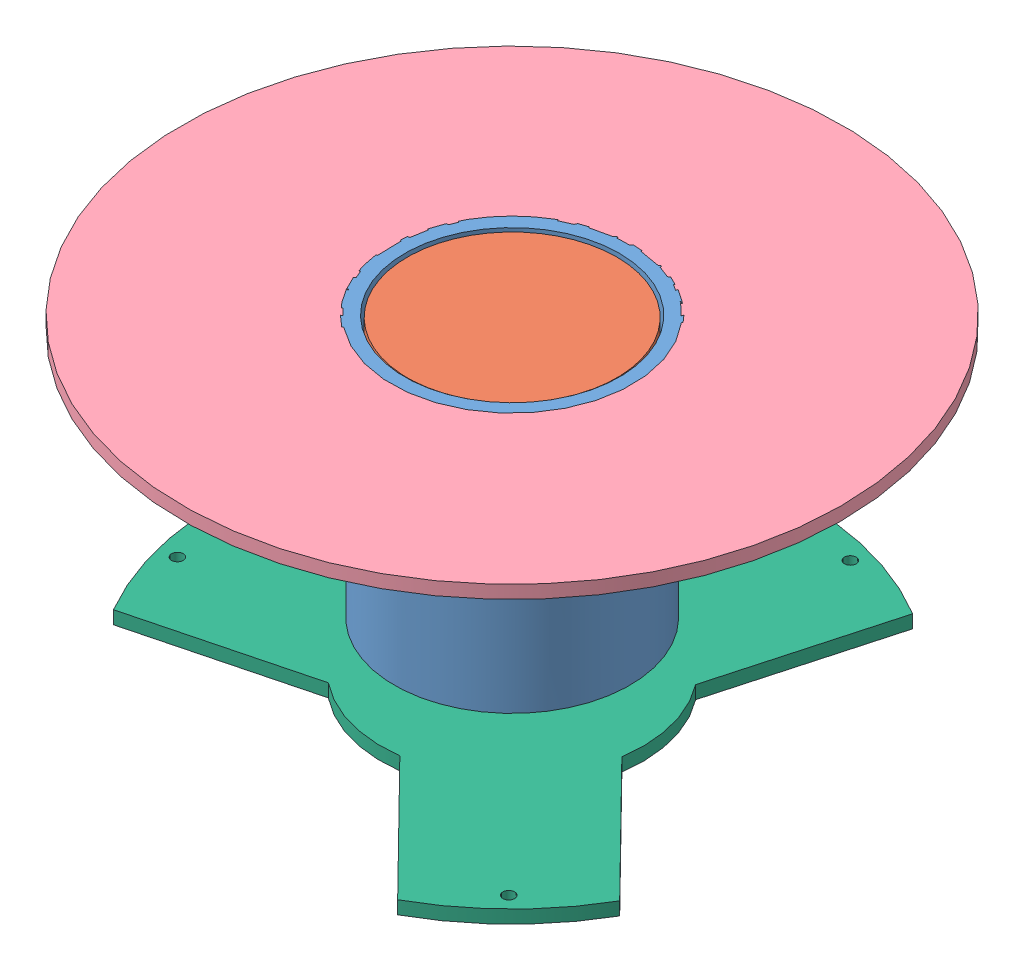
SolidWorks assembly SmallBuildSystem, configuration Default. Lengths in mm.
Overall size (310.19 197.05 310.19).
6 component instances, 6 part files, 10 mates.
Components (placement in the parent):
- SmallBuildCylinder-1: SmallBuildCylinder [Default] at origin size (92.82 100 92.82)
- 80mmBuildPlate-1: 80mmBuildPlate [Default] at (0 -15.7417 0) size (80 15 80)
- SmallBuildBase-1: SmallBuildBase [Default] at (0 -45.7417 0) x (0.949791 0 0.312884) z (-0.312884 0 0.949791) size (80 30 80)
- FillerPlate-1: FillerPlate [Default] x (0.963615 0 0.267294) z (-0.267294 0 0.963615) size (252 5 252)
- BaseRod-1: BaseRod [Default] at (0 -122.7417 0) x (-0.344051 0 -0.938951) z (0.938951 0 -0.344051) size (15 105 15)
- BuildBaseAdapter-1: BuildBaseAdapter [Default] at (0 -122.7417 0) x (0.963615 0 0.267294) z (-0.267294 0 0.963615) size (216 5 191.17)
Mates (geometry in assembly coordinates):
- Concentric1: concentric aligned: cylinder of SmallBuildCylinder-1 through (0 0 0) axis (0 -1 0) radius 41; cylinder of SmallBuildBase-1 through (0 -45.7417 0) axis (0 -1 0) radius 40
- Coincident1: coincident anti-aligned: plane of 80mmBuildPlate-1 through (0 -15.7417 0) normal (0 -1 0); plane of SmallBuildBase-1 through (0 -15.7417 0) normal (0 1 0)
- Concentric2: concentric aligned: cylinder of 80mmBuildPlate-1 through (0 -0.7417 0) axis (0 -1 0) radius 40; cylinder of SmallBuildBase-1 through (0 -45.7417 0) axis (0 -1 0) radius 40
- Coincident2: coincident aligned: plane of SmallBuildCylinder-1 through (46.4106 0 0) normal (0 1 0); plane of FillerPlate-1 through (121.4155 0 33.679) normal (0 1 0)
- Concentric3: concentric aligned: circle of SmallBuildCylinder-1; circle of FillerPlate-1
- Coincident3: coincident aligned: plane of BaseRod-1 through (0 -122.7417 0) normal (0 -1 0); plane of BuildBaseAdapter-1 through (0 -122.7417 0) normal (0 -1 0)
- Concentric4: concentric aligned: cylinder of BaseRod-1 through (0 -122.7417 0) axis (0 -1 0) radius 7.5; cylinder of BuildBaseAdapter-1 through (0 -117.7417 0) axis (0 -1 0) radius 111.5
- Concentric5: concentric aligned: cylinder of SmallBuildBase-1 through (0 -45.7417 0) axis (0 -1 0) radius 40; cylinder of BaseRod-1 through (0 -122.7417 0) axis (0 -1 0) radius 7.5
- Distance1: distance = 28 mm anti-aligned: plane of BaseRod-1 through (0 -17.7417 0) normal (0 1 0); plane of SmallBuildBase-1 through (37.9917 -45.7417 12.5154) normal (0 -1 0)
- Coincident5: coincident aligned: plane of FillerPlate-1 through (0 0 0) normal (0.963615 0 0.267294); plane of BuildBaseAdapter-1 through (0 -122.7417 0) normal (0.963615 0 0.267294)
